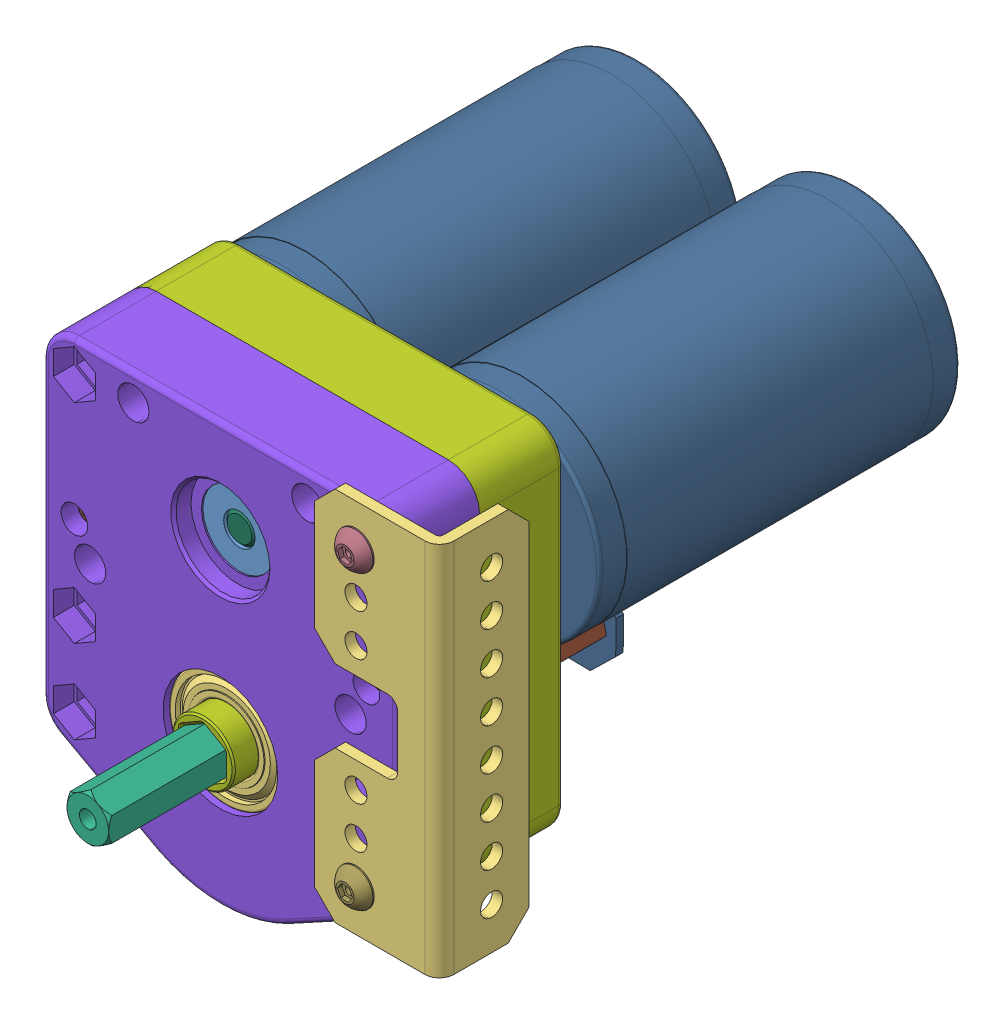
SolidWorks assembly 217-2428 wUS Digital Encoder.20121204, configuration Default. Lengths in mm.
Overall size (144.51 134.21 205.51).
82 component instances, 47 part files, 0 mates.
Components (placement in the parent):
- 217-2733-1: 217-2733 [Default] at (0 53.4162 12.0523) x (0 0 1) z (-0.971723 0.236125 0) size (7.11 24.61 24.61)
- 217-2733-2: 217-2733 [Default] at (0 53.4162 -17.6911) x (0 0 -1) z (0.971421 0.237365 0) size (7.11 24.61 24.61)
- 217-2731-1: 217-2731 [Default] at (0 0 -25.6286) x (1 0 0) z (0 -1 0) size (31.12 7.94 31.12)
- 217-2789-1: 217-2789 [Default] at (0 0 17.6784) x (0 0 -1) z (0.906537 -0.422126 0) size (11.1 38.4 38.4)
- 217-2778-001 Rev2_NCQ8A075-050M-1: 217-2778-001 Rev2_NCQ8A075-050M [Default] at (0 0 -79.4639) x (-0.681873 0.731471 0) z (0 0 1) size (31.75 33.34 41.8)
  - 217-2778-NCQ8A075-050M_NCQ8 Tube_075A-1: 217-2778-NCQ8A075-050M_NCQ8 Tube_075A [Default] at origin size (31.75 33.34 26.92)
  - 217-2778-NCQ8A075-050M_NCQ8 Rod_075M-1: 217-2778-NCQ8A075-050M_NCQ8 Rod_075M [Default] at (0 0 -6.927) x (-1 0 0) z (0 0 1) size (18.95 18.95 35.27)
  - 217-2778-NCQ8A075-050M_Snap Ring_075-1: 217-2778-NCQ8A075-050M_Snap Ring_075 [Default] at (0 0 10.362) size (21 20.74 0.97)
- 217-2428-027 Rev1_97414A630-1: 217-2428-027 Rev1_97414A630 [Default] at (0 0 -44.8925) x (0 0 1) z (0.453751 0.891129 0) size (0.64 5.89 7.9)
- 217-2788_57155K375-1: 217-2788_57155K375 [Default] at (0 0 -46.7975) x (0.971787 -0.235861 0) z (0 0 1) size (9.53 9.53 3.17)
- 217-2428-011 Rev2-1: 217-2428-011 Rev2 [Default] at (0 0 -53.992) x (0 -1 0) z (0 0 -1) size (18.03 18.03 17.56)
- 217-2428-012 Rev1-1: 217-2428-012 Rev1 [Default] at (-0.0022 -0.3376 -66.0019) x (0.999912 -0.013293 0) z (0 0 1) size (63.5 25.4 2.29)
- 217-2428-027 Rev1_97414A630-2: 217-2428-027 Rev1_97414A630 [Default] at (0 0 -48.7025) x (0 0 1) z (-0.054891 -0.998492 0) size (0.64 5.89 7.9)
- 217-2428-005 Rev1-1: 217-2428-005 Rev1 [Default] at (25.3955 -0.6753 -44.6659) x (-0.968533 0.248884 0) z (0.248884 0.968533 0) size (7.33 38.98 6.35)
- 217-2428-005 Rev1-2: 217-2428-005 Rev1 [Default] at (-25.4 0 -44.6659) x (0.661665 -0.7498 0) z (-0.7498 -0.661665 0) size (7.33 38.98 6.35)
- SCREW-B-440-0250_91306A311-1: SCREW-B-440-0250_91306A311 [Default] at (3.4925 6.0492 -45.21) x (0.999997 0.002364 0) z (0 0 1) size (5.45 5.47 5.03)
- SCREW-B-440-0250_91306A311-2: SCREW-B-440-0250_91306A311 [Default] at (3.4925 -6.0492 -45.21) x (0.883226 0.468948 0) z (0 0 1) size (5.45 5.47 5.03)
- SCREW-B-440-0250_91306A311-3: SCREW-B-440-0250_91306A311 [Default] at (-6.985 0 -45.21) size (5.45 5.47 5.03)
- SCREW-832-0375-1: SCREW-832-0375 [Default] at (25.3955 -0.6753 -68.2117) x (0 0 1) z (-0.875404 0.483392 0) size (11.73 7.92 7.92)
- SCREW-832-0375-2: SCREW-832-0375 [Default] at (-25.4 0 -68.2117) x (0 0 1) z (-0.875404 0.483392 0) size (11.73 7.92 7.92)
- SCREW-832-0375-3: SCREW-832-0375 [Default] at (25.3955 -0.6753 -20.2311) x (0 0 -1) z (1 0 0) size (11.73 7.92 7.92)
- SCREW-832-0375-4: SCREW-832-0375 [Default] at (-25.4 0 -20.2311) x (0 0 -1) z (0.999351 0.036025 0) size (11.73 7.92 7.92)
- SBS1_SBS-0632-0250-1: SBS1_SBS-0632-0250 [Default] at (15.4904 -0.5436 -61.8617) x (0 0 -1) z (0.854303 -0.519775 0) size (8.57 6.68 6.65)
- SBS1_SBS-0632-0250-2: SBS1_SBS-0632-0250 [Default] at (-15.4949 -0.1317 -61.8617) x (0 0 -1) z (0.854303 -0.519775 0) size (8.57 6.68 6.65)
- 217-2428-016 Rev2_Spur01-1: 217-2428-016 Rev2_Spur01 [Default] at (0 0 -29.2676) x (0.982225 0.187706 0) z (0 0 1) size (40.67 40.74 13.3)
- 217-2428-017 Rev2-1: 217-2428-017 Rev2 [Default] at (-12.7 -21.997 -29.2989) x (-0.40695 -0.913451 0) z (0 0 1) size (14.73 14.73 7.37)
- 217-2428-018 Rev2-1: 217-2428-018 Rev2 [Default] at (-12.7 -21.997 -39.9034) x (0.866025 -0.5 0) z (0 0 1) size (41.28 25.4 6.92)
- 217-2788_57155K375-2: 217-2788_57155K375 [Default] at (-12.7 -21.997 -34.5694) x (-0.775754 -0.631035 0) z (0 0 -1) size (9.53 9.53 3.17)
- 217-2788_57155K375-3: 217-2788_57155K375 [Default] at (-12.7 -21.997 -24.0284) x (0.47232 -0.881427 0) z (0 0 1) size (9.53 9.53 3.17)
- 217-2428-009 Rev1-1: 217-2428-009 Rev1 [Default] at (-3.6662 -34.925 -31.9659) x (-0.555959 0.831209 0) z (0.831209 0.555959 0) size (7.33 13.58 6.35)
- 217-2428-009 Rev1-2: 217-2428-009 Rev1 [Default] at (-28.4129 -20.6375 -31.9659) x (-0.555959 0.831209 0) z (0.831209 0.555959 0) size (7.33 13.58 6.35)
- SCREW-832-0250-1: SCREW-832-0250 [Default] at (-28.4129 -20.6375 -42.1132) x (0 0 1) z (-0.923728 -0.383049 0) size (8.56 7.92 7.92)
- SCREW-832-0375-5: SCREW-832-0375 [Default] at (-28.4129 -20.6375 -20.2311) x (0 0 -1) z (-0.274582 -0.961564 0) size (11.73 7.92 7.92)
- SCREW-832-0375-6: SCREW-832-0375 [Default] at (-3.6662 -34.925 -20.2311) x (0 0 -1) z (-0.826375 -0.56312 0) size (11.73 7.92 7.92)
- SCREW-832-0250-2: SCREW-832-0250 [Default] at (-3.6662 -34.925 -42.1132) x (0 0 1) z (-0.923728 -0.383049 0) size (8.56 7.92 7.92)
- PINL-0250-1125-S-1: PINL-0250-1125-S [Default] at (-12.7 -21.997 -35.3949) x (0 0 -1) z (0.874919 -0.48427 0) size (28.57 6.35 6.35)
- 217-2428-024 Rev2-1: 217-2428-024 Rev2 [Default] at (69.85 30.3575 12.8651) x (0 1 0) z (-1 0 0) size (114.3 27.31 38.1)
- SBS1_SBS1032-0500ZC-1: SBS1_SBS1032-0500ZC [Default] at (-39.6321 27.2942 -19.8755) x (0 0 -1) z (0.996655 0.081722 0) size (15.78 9.29 9.24)
- SBS1_SBS1032-0500ZC-2: SBS1_SBS1032-0500ZC [Default] at (-26.4841 76.3632 -19.8755) x (0 0 -1) z (0.751237 -0.660033 0) size (15.78 9.29 9.24)
- 217-2614-001_12t-1: 217-2614-001_12t [Default] at (-33.0581 51.8287 -4.1095) x (-0.965926 0.258819 0) z (0 0 1) size (18.29 18.29 19)
- 217-2761-001 rev1-1: 217-2761-001 rev1 [Default] at (-34.0416 48.1582 -9.5159) x (0.965926 -0.258819 0) z (0 0 1) size (2 2 20)
- SBS1_SBS1032-0500ZC-3: SBS1_SBS1032-0500ZC [Default] at (39.6321 27.2942 -19.8755) x (0 0 -1) z (0.618676 -0.785646 0) size (15.78 9.29 9.24)
- SBS1_SBS1032-0500ZC-4: SBS1_SBS1032-0500ZC [Default] at (26.4841 76.3632 -19.8755) x (0 0 -1) z (0.996655 0.081722 0) size (15.78 9.29 9.24)
- 217-2761-001 rev1-2: 217-2761-001 rev1 [Default] at (32.0746 55.4992 -9.5159) x (0.965926 0.258819 0) z (0 0 1) size (2 2 20)
- 217-2614-001_12t-2: 217-2614-001_12t [Default] at (33.0581 51.8287 -4.1095) x (0.965926 0.258819 0) z (0 0 1) size (18.29 18.29 19)
- 217-2428-001 Rev1-1: 217-2428-001 Rev1 [Default] at (0 53.4162 -25.6159) size (107.95 127.51 28.8)
- 217-2428-002 Rev1-1: 217-2428-002 Rev1 [Default] at (0 53.4162 24.9301) x (-1 0 0) z (0 0 -1) size (107.95 127.51 28.11)
- 217-2703-001-1: 217-2703-001 [Default] at (0 53.4162 4.5339) x (0.013293 -0.999912 0) z (0 0 1) size (33.29 33.29 12.65)
- 217-2707-001_40t-1: 217-2707-001_40t [Default] at (0 53.4162 -8.1661) x (-0.872595 0.488444 0) z (0 0 1) size (53.62 53.62 12.65)
- SBS1_SBS0832-1750SS-1: SBS1_SBS0832-1750SS [Default] at (-44.45 36.7075 21.4249) x (0 0 -1) z (0.052618 -0.998615 0) size (47.11 8.02 7.99)
- SBS1_SBS0832-1750SS-2: SBS1_SBS0832-1750SS [Default] at (44.45 36.7075 21.4249) x (0 0 -1) z (0.699378 -0.714752 0) size (47.11 8.02 7.99)
- SBS1_SBS2520-2000ZC-1: SBS1_SBS2520-2000ZC [Default] at (44.45 -14.0925 31.4579) x (0 0 -1) z (-0.895741 -0.444577 0) size (54.83 11.22 11.17)
- SBS1_SBS2520-1750-1: SBS1_SBS2520-1750 [Default] at (44.45 74.8075 31.4579) x (0 0 -1) z (0.959597 0.281377 0) size (48.48 11.22 11.17)
- Nylock Nut_NNY2520-ZC-1: Nylock Nut_NNY2520-ZC [Default] at (44.45 -14.0925 -17.7546) x (-0.164279 0.986414 0) z (0 0 -1) size (12.85 11.89 7.62)
- Nylock Nut_NNY2520-ZC-2: Nylock Nut_NNY2520-ZC [Default] at (44.45 74.8075 -17.7546) x (0 1 0) z (0 0 -1) size (12.85 11.89 7.62)
- 217-2428-004 Rev3-1: 217-2428-004 Rev3 [Default] at (0 53.4162 -2.8448) x (-0.511468 0.859302 0) z (0 0 1) size (11 9.53 43.92)
- 217-2428-021 Rev1-1: 217-2428-021 Rev1 [Default] at (0 53.4162 -16.1036) x (0.426322 -0.904572 0) z (0 0 1) size (15.88 15.88 3.17)
- 217-2428-029 Rev1-1: 217-2428-029 Rev1 [Default] at (0 53.4162 11.4173) size (15.88 15.88 1.12)
- Nylock 8-32-1: Nylock 8-32 [Default] at (44.45 36.7075 -19.2659) x (0.254216 0.967147 0) z (-0.967147 0.254216 0) size (10.2 4.9 8.12)
- Nylock 8-32-2: Nylock 8-32 [Default] at (-44.45 36.7075 -19.2659) x (0.948441 0.316954 0) z (-0.316954 0.948441 0) size (10.2 4.9 8.12)
- 217-2792-001 Rev1-1: 217-2792-001 Rev1 [Default] at (0 0 -25.5778) x (0 1 0) z (0 0 1) size (82.92 82.92 116)
  - 217-2428-008 Rev1-1: 217-2428-008 Rev1 [Default] at (0 0 10.2679) size (31.75 31.75 1.59)
  - 217-2428-028 Rev1_97633A250-1: 217-2428-028 Rev1_97633A250 [Default] at (0 0 37.1221) x (0 0 1) z (0.9357 -0.352797 0) size (1.07 23.39 21.18)
  - 217-2709-101 Rev1-1: 217-2709-101 Rev1 [Default] at (0 0 20.7137) x (0.993517 0.113685 0) z (0 0 -1) size (62.31 62.31 12.7)
    - 217-2428-022 Rev1-1: 217-2428-022 Rev1 [Default] at origin size (28.57 28.57 6.1)
    - 217-2709-001_44t Steel-1: 217-2709-001_44t Steel [Default] at (0 0 3.302) x (0.062728 -0.998031 0) z (0 0 1) size (58.74 58.74 11.11)
  - 217-2713-101 Rev1-1: 217-2713-101 Rev1 [Default] at (0 0 33.4137) x (-0.01285 0.999917 0) z (0 0 -1) size (81.88 81.88 12.7)
    - 217-2713-001_60t Steel-1: 217-2713-001_60t Steel [Default] at (0 0 3.302) x (0.999266 -0.038302 0) z (0 0 1) size (78.91 78.91 11.11)
    - 217-2428-022 Rev1-1: 217-2428-022 Rev1 [Default] at origin size (28.57 28.57 6.1)
  - 217-2790-001 Rev1-1: 217-2790-001 Rev1 [Default] x (-1 0 0) z (0 0 1) size (22.23 22.23 116)
    - 217-2790-002 Rev1-1: 217-2790-002 Rev1 [Default] at (0 0 62.9285) x (0 0 1) z (1 0 0) size (55.88 12.7 16.13)
    - 217-2790-003 Rev1-1: 217-2790-003 Rev1 [Default] at origin size (22.23 22.23 55.94)
    - 217-2790-004 Rev1-1: 217-2790-004 Rev1 [Default] at (0 0 14.3911) x (0.928141 0.372229 0) z (0 0 1) size (11.68 11.68 44.12)
  - 217-2428-007 Rev1-1: 217-2428-007 Rev1 [Default] at (6.3246 0 14.2494) x (0.485433 0.3648 -0.794529) z (-0.690104 -0.398066 -0.6044) size (6.35 6.35 6.35)
  - 217-2428-007 Rev1-2: 217-2428-007 Rev1 [Default] at (9.017 0 26.9494) x (0.741485 -0.614816 -0.268704) z (-0.150074 0.23836 -0.959512) size (6.35 6.35 6.35)
  - 217-2428-007 Rev1-3: 217-2428-007 Rev1 [Default] at (-3.1623 5.4773 14.2494) x (-0.558642 0.237997 -0.794529) z (0.689788 -0.398615 -0.6044) size (6.35 6.35 6.35)
  - 217-2428-007 Rev1-4: 217-2428-007 Rev1 [Default] at (-3.1623 -5.4773 14.2494) x (0.073209 -0.602797 -0.794529) z (0.000317 0.796681 -0.6044) size (6.35 6.35 6.35)
  - 217-2428-007 Rev1-5: 217-2428-007 Rev1 [Default] at (-4.5085 7.809 26.9494) x (0.161703 0.949553 -0.268704) z (-0.131389 -0.249147 -0.959512) size (6.35 6.35 6.35)
  - 217-2428-007 Rev1-6: 217-2428-007 Rev1 [Default] at (-4.5085 -7.809 26.9494) x (-0.903188 -0.334737 -0.268704) z (0.281462 0.010788 -0.959512) size (6.35 6.35 6.35)
- 217-2000-1: 217-2000 [Default] at (33.0581 51.8287 -25.6159) x (0 0 -1) z (0.965926 0.258819 0) size (150.2 64.01 64.01)
- 217-2000-2: 217-2000 [Default] at (-33.0581 51.8287 -25.6159) x (0 0 -1) z (-0.965926 0.258819 0) size (150.2 64.01 64.01)
- E4P-X-250-X-D-D-D-X-1: E4P-X-250-X-D-D-D-X [Default] at (-12.7 -21.997 -39.9034) x (0.5 0.866025 0) z (-0.866025 0.5 0) size (24.87 14.38 22.9)
